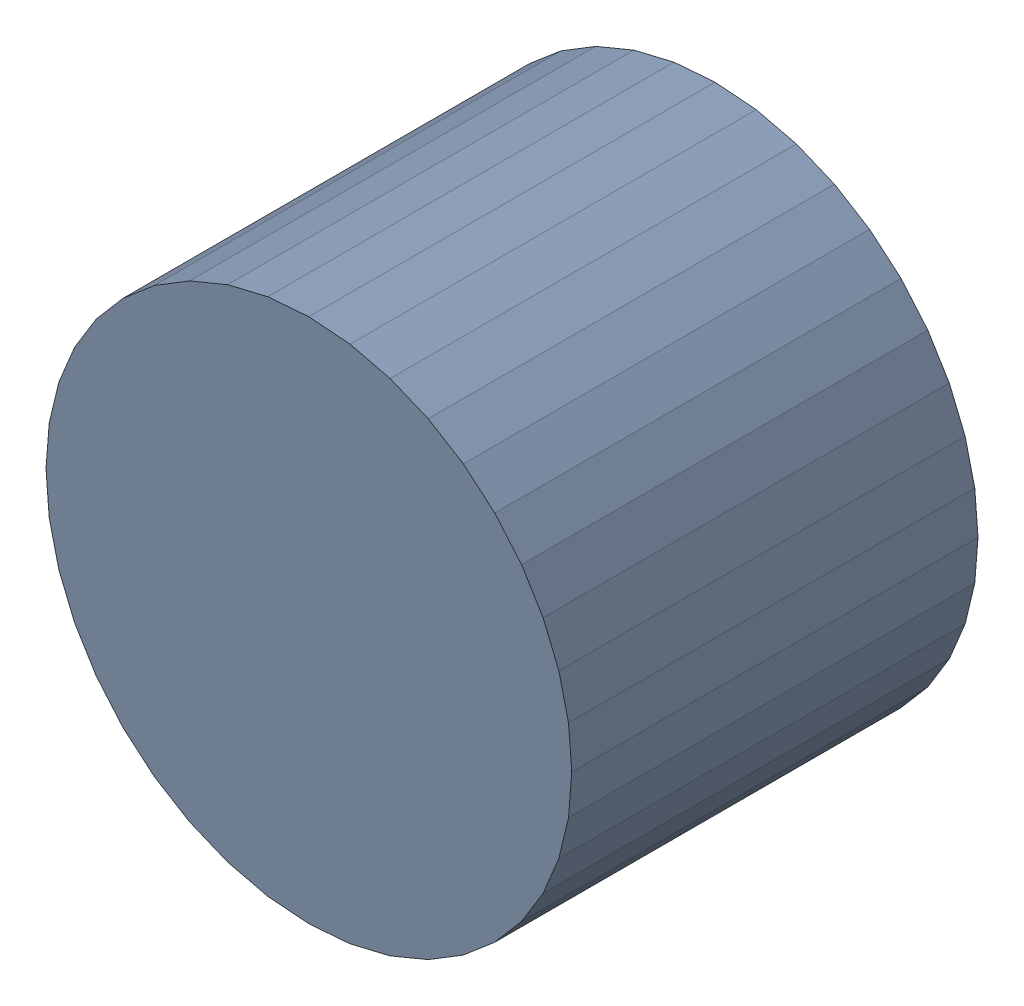
SolidWorks assembly C17Kanaloa_v2.0.0_Power, configuration Default. Lengths in mm.
Overall size (8.02 8.02 6.2).
2 component instances, 1 part files, 0 mates.
Components (placement in the parent):
- 425994496-1: 425994496 [Default] at (69.317 160.68 0) size (8.02 8.02 6.2)
  - Extruded_22-1: Extruded_22 [Default] at origin size (8.02 8.02 6.2)
